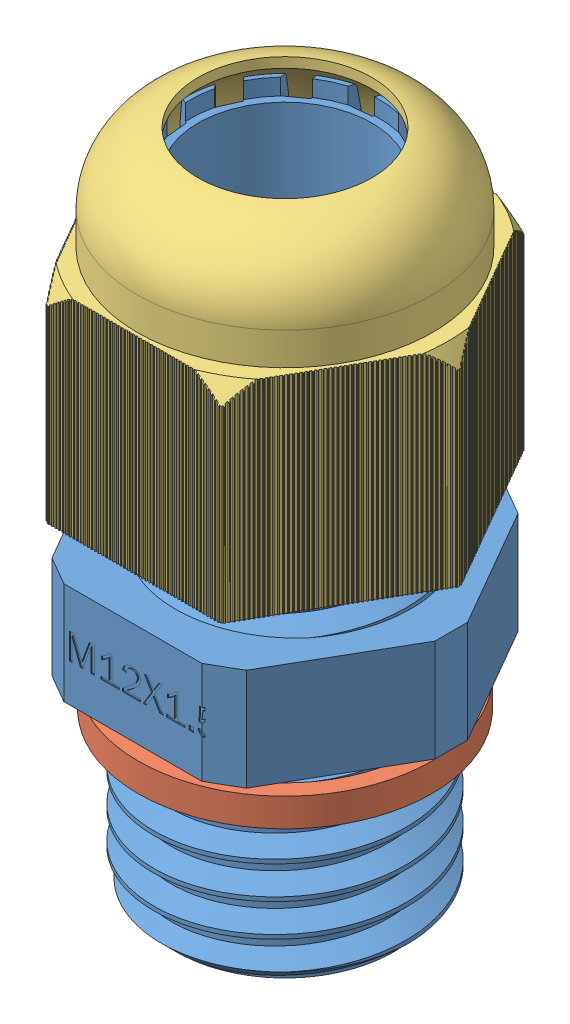
SolidWorks assembly M12x1.5 Cable gland, configuration Default. Lengths in mm.
Overall size (16.05 30.89 14).
3 component instances, 3 part files, 5 mates.
Components (placement in the parent):
- Cable gland-1: Cable gland [Default] at origin size (15.3 29.83 14)
- Rubber gasket-1: Rubber gasket [Default] at (0 -6.81 0) x (-1 0 0) z (0 0 1) size (13.5 1.3 13.5)
- M12 Domed nut-1: M12 Domed nut [Default] at (0 6.2 0) size (16.05 14.26 14)
Mates (geometry in assembly coordinates):
- Concentric2: concentric anti-aligned: cylinder of Cable gland-1 through (0 -14.65 0) axis (0 1 0) radius 4; cylinder of Rubber gasket-1 through (0 -6.16 0) axis (0 -1 0) radius 6
- Concentric3: concentric aligned: cylinder of Cable gland-1 through (0 -14.65 0) axis (0 1 0) radius 4; cylinder of M12 Domed nut-1 through (0 61.2 0) axis (0 1 0) radius 4
- Distance1: distance = 0.91 mm anti-aligned: plane of Cable gland-1 through (0 -5.25 0) normal (0 -1 0); plane of Rubber gasket-1 through (0 -6.16 0) normal (0 1 0)
- Distance3: distance = 2 mm anti-aligned: plane of Cable gland-1 through (0 -0.55 0) normal (0 1 0); plane of M12 Domed nut-1 through (0 1.45 0) normal (0 -1 0)
- Distance4: distance = 3.1 mm anti-aligned: plane of EL-CG12-14 Cable gland-1 through (0 -5.25 0) normal (0 -1 0); plane of EL-CG12-12 Rubber gasket-1 through (0 -6.16 0) normal (0 1 0)
